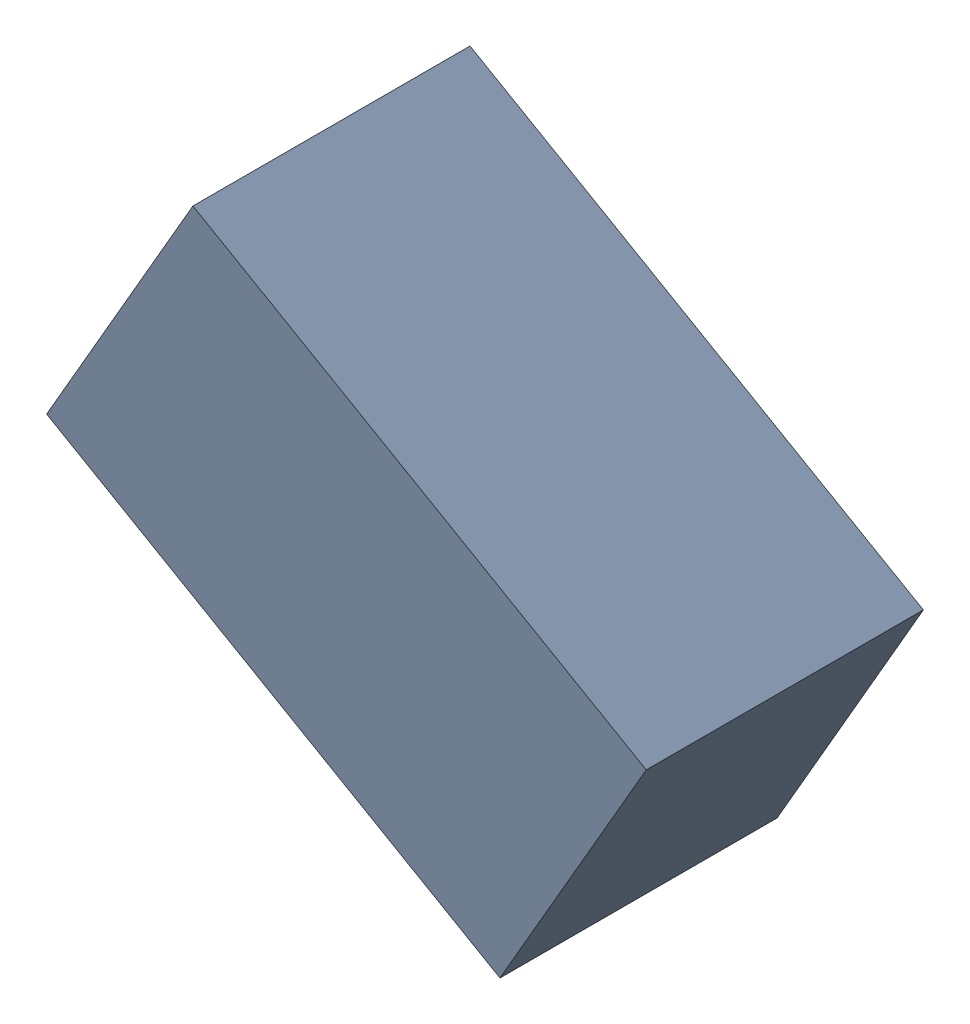
SolidWorks assembly R2_TDA6, configuration Standard. Lengths in mm.
Overall size (1.95 1.67 0.9).
2 component instances, 1 part files, 0 mates.
Components (placement in the parent):
- 885544144-1: 885544144 [Standard] at (-48.1169 23.4516 0) size (1.95 1.67 0.9)
  - Extruded_14-1: Extruded_14 [Standard] at origin size (1.95 1.67 0.9)
